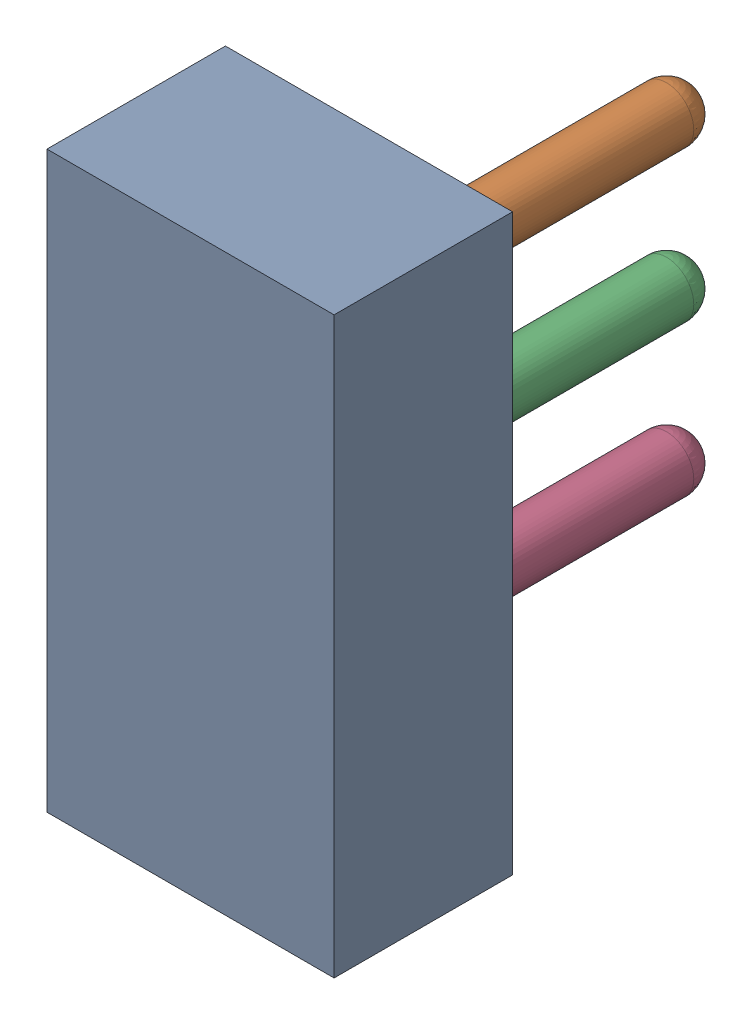
SolidWorks assembly Open CASCADE STEP translator 6.8 1.9.1, configuration Défaut. Lengths in mm.
Overall size (4.83 9.65 8.46).
4 component instances, 4 part files, 0 mates.
Components (placement in the parent):
- Body_1_6-1: Body_1_6 [Défaut] at origin size (4.83 9.65 3)
- Pin_1_3-1: Pin_1_3 [Défaut] x (0 -1 0) z (0 0 1) size (0.92 0.92 7.42)
- Pin_2_3-1: Pin_2_3 [Défaut] at (2.54 -2.54 0) x (0 -1 0) z (0 0 1) size (0.92 0.92 7.42)
- Pin_3_2-1: Pin_3_2 [Défaut] at (5.08 -5.08 0) x (0 -1 0) z (0 0 1) size (0.92 0.92 7.42)
